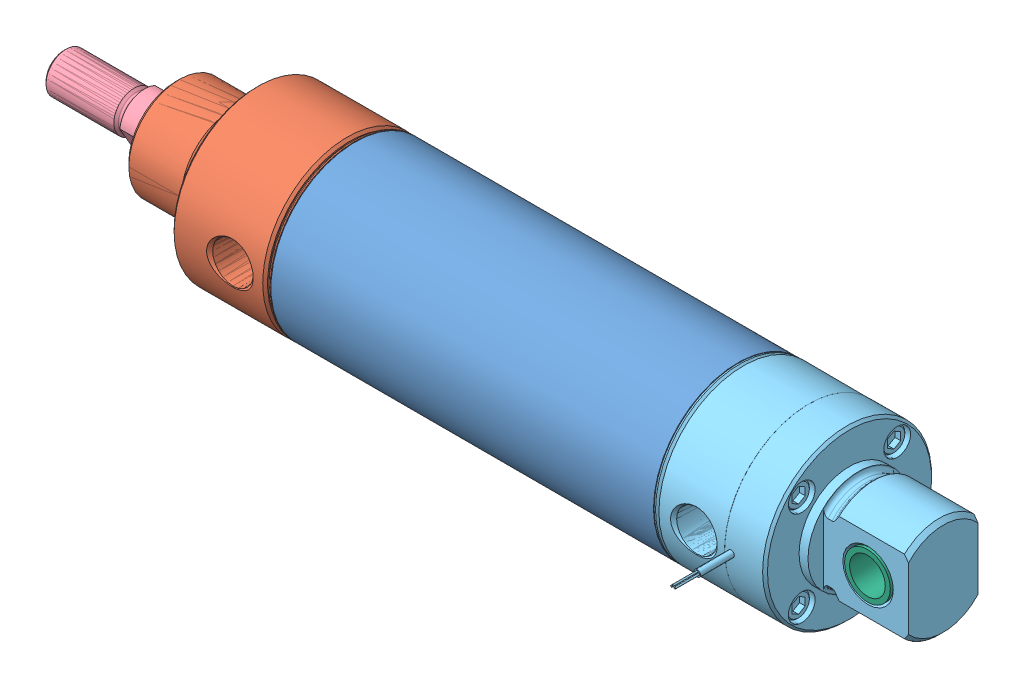
SolidWorks assembly PFC-313-X, configuration Default. Lengths in mm.
Overall size (276.35 53.09 71.29).
7 component instances, 7 part files, 18 mates.
Components (placement in the parent):
- PFC-313-X_0_dummy-1: PFC-313-X_0_dummy [Default] at origin
- PFC-31-3-1: PFC-31-3 [Default] at (104.6734 0 0) size (122.88 52.98 52.98)
- PFC-31X-_0_rod_guide-1: PFC-31X-_0_rod_guide [Default] at (-38.8874 0 0) x (-1 0 0) z (0 0 1) size (64.29 53.09 53.09)
- PFC-313-X__rod-1: PFC-313-X__rod [Default] at (-43.7642 0 0) size (170.66 50.9 50.9)
- PFCN-313-0_31_stud-1: PFCN-313-0_31_stud [Default] at (-43.7642 0 0) x (-1 0 0) z (0 0 1) size (55.58 15.7 15.61)
- PFC-31X-1: PFC-31X [Default] at (147.5486 0 0) size (72.34 53.09 71.29)
- D-8342-XX-1: D-8342-XX [Default] at (164.3126 0 0) x (1 0 0) z (0 0 -1) size (14.35 14.35 22.23)
Mates (geometry in assembly coordinates):
- Distance1: distance = 0 mm anti-aligned: plane of PFC-31-3-1 through (0 0 0) normal (-1 0 0); plane of PFC-313-X_0_dummy-1 through (0 0 0) normal (1 0 0)
- Coincident1: coincident anti-aligned: line of PFC-313-X_0_dummy-1 through (80.9 0 0) axis (-1 0 0); line of PFC-31-3-1 through (23.7734 0 0) axis (1 0 0)
- Angle3: planar angle = 0 rad aligned: plane of PFC-31-3-1 through (104.6734 0 0) normal (0 0 -1); plane of PFC-313-X_0_dummy-1 through (0 0 0) normal (0 0 -1)
- Distance2: distance = 0 mm anti-aligned: plane of PFC-31X-_0_rod_guide-1; plane of PFC-31-3-1 through (0 0 0) normal (1 0 0)
- Coincident2: coincident anti-aligned: line of PFC-31-3-1 through (185.5734 0 0) axis (-1 0 0); line of PFC-31X-_0_rod_guide-1 through (-119.7874 0 0) axis (1 0 0)
- Angle6: planar angle = 0 rad aligned: plane of PFC-31X-_0_rod_guide-1 through (-38.8874 0 0) normal (0 0 -1); plane of PFC-31-3-1 through (104.6734 0 0) normal (0 0 -1)
- LimitDistance1: limit distance = 0 mm anti-aligned: plane of PFC-313-X__rod-1 through (-64.2874 0 0) normal (-1 0 0); plane of PFC-31X-_0_rod_guide-1
- Coincident3: coincident anti-aligned: line of PFC-31X-_0_rod_guide-1 through (42.0126 0 0) axis (-1 0 0); line of PFC-313-X__rod-1 through (-124.6642 0 0) axis (1 0 0)
- Angle9: planar angle = 0 rad aligned: plane of PFC-313-X__rod-1 through (-43.7642 0 0) normal (0 0 -1); plane of PFC-31X-_0_rod_guide-1 through (-38.8874 0 0) normal (0 0 -1)
- Distance3: distance = 0 mm anti-aligned: plane of PFCN-313-0_31_stud-1; plane of PFC-313-X__rod-1 through (-64.2874 0 0) normal (1 0 0)
- Coincident4: coincident anti-aligned: line of PFC-313-X__rod-1 through (37.1358 0 0) axis (-1 0 0); line of PFCN-313-0_31_stud-1 through (-124.6642 0 0) axis (1 0 0)
- Angle12: planar angle = 0 rad aligned: plane of PFCN-313-0_31_stud-1 through (-43.7642 0 0) normal (0 0 -1); plane of PFC-313-X__rod-1 through (-43.7642 0 0) normal (0 0 -1)
- Distance4: distance = 0 mm anti-aligned: plane of PFC-31X-1 through (104.6734 0 0) normal (1 0 0); plane of PFC-31-3-1 through (104.6734 0 0) normal (-1 0 0)
- Coincident5: coincident anti-aligned: line of PFC-31-3-1 through (23.7734 0 0) axis (1 0 0); line of PFC-31X-1 through (228.4486 0 0) axis (-1 0 0)
- Angle15: planar angle = 0 rad aligned: plane of PFC-31X-1 through (147.5486 0 0) normal (0 0 -1); plane of PFC-31-3-1 through (104.6734 0 0) normal (0 0 -1)
- Distance5: distance = 0 mm anti-aligned: plane of D-8342-XX-1 through (164.3126 0 0) normal (0 0 -1); plane of PFC-31X-1 through (147.5486 0 0) normal (0 0 1)
- Coincident6: coincident anti-aligned: line of PFC-31X-1 through (164.3126 0 80.9) axis (0 0 -1); line of D-8342-XX-1 through (164.3126 0 -80.9) axis (0 0 1)
- Angle18: planar angle = 0 rad aligned: plane of D-8342-XX-1; plane of PFC-31X-1 through (164.3126 0 0) normal (1 0 0)
